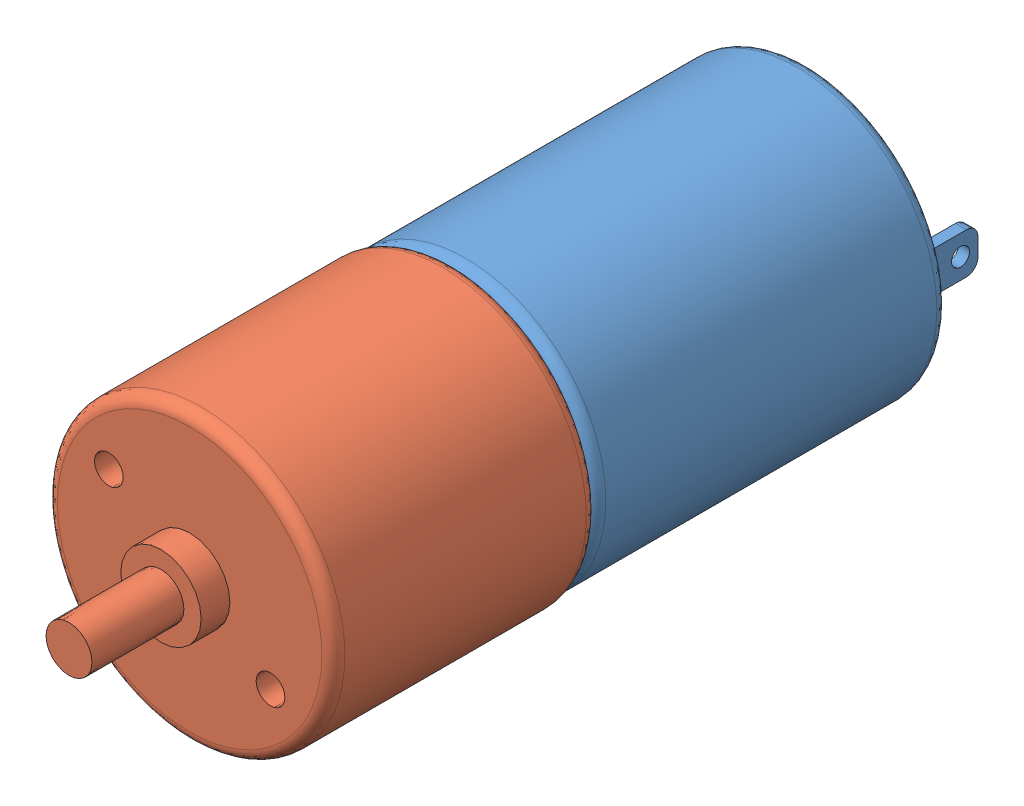
SolidWorks assembly Motor, configuration Valor predeterminado. Lengths in mm.
Overall size (25 25 69.3).
2 component instances, 2 part files, 3 mates.
Components (placement in the parent):
- Motor-1: Motor [Valor predeterminado] at (-6.4714 0.7429 0) size (24.4 24.4 45.8)
- Motor_Redutor-1: Motor_Redutor [Valor predeterminado] at (-6.4714 0.7429 30.8) size (25 25 33.5)
Mates (geometry in assembly coordinates):
- Coincidente1: coincident anti-aligned: plane of Motor-1 through (-6.4714 0.7429 30.8) normal (0 0 1); plane of Motor_Redutor-1 through (-6.4714 0.7429 30.8) normal (0 0 -1)
- Coincidente2: coincident aligned: plane of Motor-1 through (-6.4714 0.7429 0) normal (0 1 0); plane of Motor_Redutor-1 through (-6.4714 0.7429 30.8) normal (0 1 0)
- Concêntrico2: concentric aligned: cylinder of Motor-1 through (-6.4714 0.7429 40.8) axis (0 0 -1) radius 2; cylinder of Motor_Redutor-1 through (-6.4714 0.7429 64.3) axis (0 0 -1) radius 2
